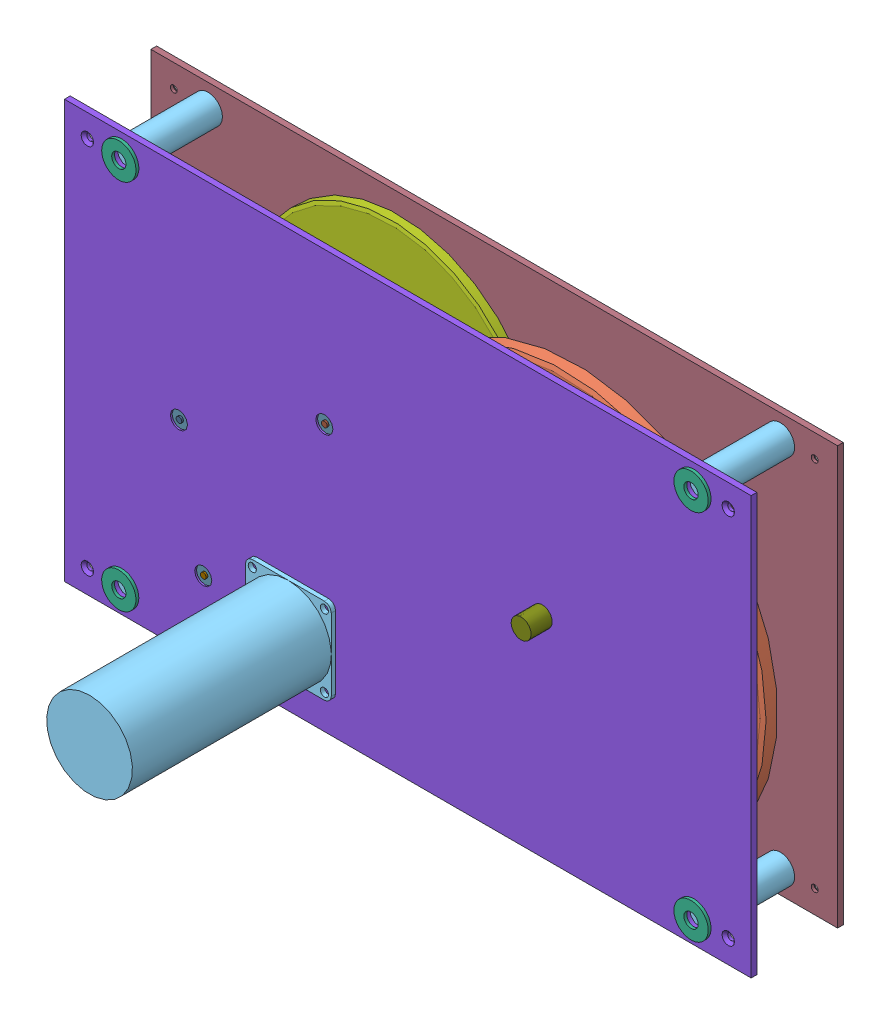
SolidWorks assembly Сборка1, configuration Полный. Lengths in mm.
Overall size (240 146 116.22).
42 component instances, 24 part files, 82 mates.
Components (placement in the parent):
- z1-1: z1 [Полный] at (79.7654 26 -7) x (-1 0 0) z (0 1 0) size (12.5 6 12.5)
- z2-1: z2 [Полный] at (48.5154 26 -3.75) x (1 0 0) z (0 1 0) size (51 8.48 51)
- z3-1: z3 [Полный] at (48.5154 26 -16.75) x (-1 0 0) z (0 1 0) size (13.5 6 13.5)
- z4-1: z4 [Полный] at (40 68.9133 -17) x (1 0 0) z (0 -1 0) size (75 7 75)
- ДПР-1: ДПР [Полный] at (79.7654 26 73) x (0 0 -1) z (0 1 0) size (84.5 30 30)
- z5-1: z5 [Полный] at (40 68.9133 -24) x (-1 0 0) z (0 1 0) size (13.5 6 13.5)
- z6-1: z6 [Полный] at (90.832 93 -24.25) x (-1 0 0) z (0 1 0) size (101 7 101)
- list1-1: list1 [Полный] at origin size (240 146 2)
- val2-1: val2 [Полный] at (48.5154 26 -31) size (7 7 32.21)
- val3-1: val3 [Полный] at (40 68.9133 -31) size (7 7 32.21)
- val4-1: val4 [Полный] at (90.832 93 -32.4148) x (0.998801 -0.04895 0) z (0 0 1) size (7 7 32.21)
- z7-1: z7 [Полный] at (90.832 93 -9.65) x (1 0 0) z (0 -1 0) size (18.9 8.4 18.9)
- list2-1: list2 [Полный] at (0 0 -30.2135) size (240 146 2)
- подш2-1: подш2 [Полный] at (48.5154 26 -0.6) x (0.999616 -0.027714 0) z (0 0 1) size (7.2 7.2 2)
- подш2-2: подш2 [Полный] at (40 68.9133 -0.6) x (0.987241 -0.15923 0) z (0 0 1) size (7.2 7.2 2)
- подш2-3: подш2 [Полный] at (90.832 93 -0.6) x (0.993287 -0.11568 0) z (0 0 1) size (7.2 7.2 2)
- подш2-5: подш2 [Полный] at (167 73 -0.6) x (0.605426 0.795902 0) z (0 0 1) size (7.2 7.2 2)
- подш2-6: подш2 [Полный] at (90.832 93 -27.6135) x (-0.923728 -0.383049 0) z (0 0 -1) size (7.2 7.2 2)
- подш2-7: подш2 [Полный] at (40 68.9133 -27.6135) x (-0.923728 -0.383049 0) z (0 0 -1) size (7.2 7.2 2)
- подш2-8: подш2 [Полный] at (48.5154 26 -27.6135) x (-0.923728 -0.383049 0) z (0 0 -1) size (7.2 7.2 2)
- mufta-1: mufta [Полный] at (167 73 -73.8912) x (0 0 -1) z (-1 0 0) size (51 141.4 141.4)
  - prushina-1: prushina [Полный] at (-61.987 0 0) x (0 0.715642 0.698468) z (1 0 0) size (18.92 18.98 26.11)
  - val5-1: val5 [Полный] at (-73.2912 0 0) x (0 -0.973244 -0.229772) z (1 0 0) size (15 15 51)
  - vt1-1: vt1 [Полный] at (-41.3486 0 0) x (0 -1 0) z (0 0 1) size (30 6 30)
  - vt2-1: vt2 [Полный] at (-56.8912 0 0) x (0 1 0) z (0 0 1) size (31 6 31)
  - disk-1: disk [Полный] at (-63.8912 0 0) x (0 0.969939 -0.24335) z (1 0 0) size (30 30 1)
  - подш2-1: подш2 [Полный] at (-35.2912 0 0) x (0 1 0) z (1 0 0) size (7.2 7.2 2)
  - z8-1: z8 [Полный] at (-63.8912 0 0) x (0 1 0) z (0 0 1) size (141.4 4.9 141.4)
- stakan-1: stakan [Полный] at (167 73 -28.566) x (1 0 0) z (0 1 0) size (48.86 14.66 48.86)
- гайка-1: гайка [Полный] at (79.7654 26 -8.1) x (0 0 1) z (-1 0 0) size (2.2 7 6.06)
- stoika-5: stoika [Полный] at (20 8 -28.2135) x (1 0 0) z (0 -1 0) size (10 28.21 10)
- stoika-6: stoika [Полный] at (20 138 -28.2135) x (1 0 0) z (0 -1 0) size (10 28.21 10)
- stoika-7: stoika [Полный] at (220 138 -28.2135) x (1 0 0) z (0 -1 0) size (10 28.21 10)
- stoika-8: stoika [Полный] at (220 8 -28.2135) x (1 0 0) z (0 -1 0) size (10 28.21 10)
- диск-1: диск [Полный] at (220 138 -31.2135) size (12 12 1)
- диск-2: диск [Полный] at (20 138 -31.2135) size (12 12 1)
- диск-3: диск [Полный] at (20 8 -31.2135) size (12 12 1)
- диск-4: диск [Полный] at (220 8 -31.2135) size (12 12 1)
- диск-5: диск [Полный] at (220 8 2) size (12 12 1)
- диск-6: диск [Полный] at (220 138 2) size (12 12 1)
- диск-7: диск [Полный] at (20 138 2) size (12 12 1)
- диск-8: диск [Полный] at (20 8 2) x (0.432232 0.901762 0) z (0 0 1) size (12 12 1)
Mates (geometry in assembly coordinates):
- Концентричный3: concentric aligned: cylinder of z2-1 through (48.5154 26 -10.75) axis (0 0 1) radius 2; cylinder of z3-1 through (48.5154 26 -16.75) axis (0 0 1) radius 2
- Концентричный5: concentric anti-aligned: cylinder of z4-1 through (40 68.9133 -10) axis (0 0 -1) radius 2; cylinder of z5-1 through (40 68.9133 -24) axis (0 0 1) radius 2
- Ширина2: width anti-aligned: plane of z3-1 through (48.5154 26 -16.75) normal (0 0 -1); plane of z4-1 through (41.7654 26 -13.75) normal (0 0 1); plane of z3-1 through (77.5 68.9133 -13.5) normal (0 0 1); plane of z4-1 through (40 68.9133 -17) normal (0 0 -1)
- Ширина3: width anti-aligned: plane of z5-1 through (40 68.9133 -24) normal (0 0 -1); plane of z6-1 through (33.25 68.9133 -21) normal (0 0 1); plane of z5-1 through (90.832 93 -24.25) normal (0 0 -1); plane of z6-1 through (40.332 93 -20.75) normal (0 0 1)
- Параллельность1: parallel aligned: plane of ДПР-1 through (64.7654 11 3.5) normal (-1 0 0); plane of list1-1 through (0 0 2) normal (-1 0 0)
- Совпадение6: coincident anti-aligned: plane of z1-1 through (76.7654 26 -1) normal (0 0 1); plane of ДПР-1 through (75.2535 26 -1) normal (0 0 -1)
- Концентричный6: concentric aligned: cylinder of z1-1 through (79.7654 26 -7) axis (0 0 1) radius 2; cylinder of ДПР-1 through (79.7654 26 73) axis (0 0 1) radius 2
- Совпадение7: coincident anti-aligned: plane of ДПР-1 through (64.7654 26 2) normal (0 0 -1); plane of list1-1 through (0 0 2) normal (0 0 1)
- Концентричный8: concentric aligned: cylinder of list1-1 through (48.5154 26 2) axis (0 0 -1) radius 3; cylinder of val2-1 through (48.5154 26 5.0569) axis (0 0 -1) radius 2
- Совпадение8: coincident aligned: plane of list1-1 through (0 0 2) normal (0 0 1); plane of val2-1 through (0 0 2) normal (0 0 1)
- Концентричный9: concentric anti-aligned: cylinder of z2-1 through (48.5154 26 -10.75) axis (0 0 1) radius 2; cylinder of val2-1 through (48.5154 26 5.0569) axis (0 0 -1) radius 2
- Ширина4: width anti-aligned: plane of z2-1 through (74.0154 26 -7.25) normal (0 0 -1); plane of z1-1 through (48.5154 26 -3.75) normal (0 0 1); plane of z2-1 through (73.5154 26 -4) normal (0 0 1); plane of z1-1 through (79.7654 26 -7) normal (0 0 -1)
- Совпадение9: coincident aligned: plane of list1-1 through (0 0 2) normal (0 0 1); plane of val3-1 through (0 0 2) normal (0 0 1)
- Концентричный14: concentric aligned: cylinder of z4-1 through (40 68.9133 -10) axis (0 0 -1) radius 2; cylinder of val3-1 through (40 68.9133 5.0569) axis (0 0 -1) radius 2
- Концентричный15: concentric anti-aligned: cylinder of z5-1 through (40 68.9133 -18) axis (0 0 1) radius 3; cylinder of val3-1 through (40 68.9133 5.0569) axis (0 0 -1) radius 2
- Концентричный16: concentric anti-aligned: cylinder of z6-1 through (90.832 93 -17.25) axis (0 0 1) radius 3; cylinder of val4-1 through (90.832 93 5.0569) axis (0 0 -1) radius 2
- Концентричный17: concentric anti-aligned: cylinder of val4-1 through (90.832 93 5.0569) axis (0 0 -1) radius 2; cylinder of z7-1 through (90.832 93 -1.25) axis (0 0 1) radius 3
- Совпадение12: coincident anti-aligned: plane of list1-1 through (0 0 0) normal (0 0 -1)
- Совпадение13: coincident anti-aligned: plane of list1-1 through (0 0 2) normal (0 -1 0)
- Совпадение14: coincident anti-aligned: plane of list1-1 through (0 0 2) normal (-1 0 0)
- Концентричный19: concentric anti-aligned: cylinder of val2-1 through (48.5154 26 -33.042) axis (0 0 1) radius 1; cylinder of list2-1 through (48.5154 26 -28.2135) axis (0 0 -1) radius 3
- Концентричный20: concentric anti-aligned: cylinder of val3-1 through (40 68.9133 -33.042) axis (0 0 1) radius 1; cylinder of list2-1 through (40 68.9133 -28.2135) axis (0 0 -1) radius 3
- Концентричный21: concentric aligned: cylinder of val2-1 through (48.5154 26 4.8284) axis (0 0 -1) radius 1; cylinder of подш2-1 through (48.5154 26 1.4) axis (0 0 -1) radius 3
- Совпадение16: coincident aligned: plane of list1-1 through (0 0 0) normal (0 0 -1); circle of подш2-1
- Концентричный22: concentric aligned: cylinder of val3-1 through (40 68.9133 4.8284) axis (0 0 -1) radius 1; cylinder of подш2-2 through (40 68.9133 1.4) axis (0 0 -1) radius 3
- Совпадение17: coincident anti-aligned: plane of list1-1 through (0 0 0) normal (0 0 -1); plane of подш2-2 through (40 68.9133 0) normal (0 0 1)
- Концентричный23: concentric aligned: cylinder of val4-1 through (90.832 93 4.8284) axis (0 0 -1) radius 1; cylinder of подш2-3 through (90.832 93 1.4) axis (0 0 -1) radius 3
- Совпадение18: coincident anti-aligned: plane of list1-1 through (0 0 0) normal (0 0 -1); plane of подш2-3 through (90.832 93 0) normal (0 0 1)
- Концентричный26: concentric aligned: cylinder of val4-1 through (90.832 93 -33.042) axis (0 0 1) radius 1; cylinder of подш2-6 through (90.832 93 -29.6135) axis (0 0 1) radius 3
- Совпадение21: coincident anti-aligned: plane of list2-1 through (0 0 -28.2135) normal (0 0 1); plane of подш2-6 through (90.832 93 -28.2135) normal (0 0 -1)
- Концентричный28: concentric aligned: cylinder of val3-1 through (40 68.9133 -33.042) axis (0 0 1) radius 1; cylinder of подш2-7 through (40 68.9133 -29.6135) axis (0 0 1) radius 3
- Совпадение22: coincident anti-aligned: plane of list2-1 through (0 0 -28.2135) normal (0 0 1); plane of подш2-7 through (40 68.9133 -28.2135) normal (0 0 -1)
- Концентричный30: concentric aligned: cylinder of val2-1 through (48.5154 26 -33.042) axis (0 0 1) radius 1; cylinder of подш2-8 through (48.5154 26 -29.6135) axis (0 0 1) radius 3
- Совпадение23: coincident anti-aligned: plane of list2-1 through (0 0 -28.2135) normal (0 0 1); plane of подш2-8 through (48.5154 26 -28.2135) normal (0 0 -1)
- Параллельность2: parallel aligned: plane of z1-1 through (79.7654 26 -7) normal (0 1 0); plane of list1-1 through (0 146 2) normal (0 1 0)
- Параллельность3: parallel aligned: plane of z2-1 through (48.5154 26 -3.75) normal (0 1 0); plane of list1-1 through (0 146 2) normal (0 1 0)
- Параллельность4: parallel aligned: plane of z3-1 through (48.5154 26 -16.75) normal (0 1 0); plane of list1-1 through (0 146 2) normal (0 1 0)
- Параллельность5: parallel anti-aligned: plane of z4-1 through (40 68.9133 -17) normal (0 -1 0); plane of list1-1 through (0 146 2) normal (0 1 0)
- Параллельность6: parallel aligned: plane of z5-1 through (40 68.9133 -24) normal (0 1 0); plane of list1-1 through (0 146 2) normal (0 1 0)
- Параллельность7: parallel aligned: plane of z6-1 through (90.832 93 -24.25) normal (0 1 0); plane of list1-1 through (0 146 2) normal (0 1 0)
- Параллельность8: parallel anti-aligned: plane of list1-1 through (0 146 2) normal (0 1 0); plane of z7-1 through (90.832 93 -9.65) normal (0 -1 0)
- Концентричный31: concentric aligned: cylinder of list1-1 through (167 73 2) axis (0 0 -1) radius 3; cylinder of mufta-1/val5-1 through (167 73 9.4) axis (0 0 -1) radius 3.5
- Ширина6: width anti-aligned: plane of mufta-1/z8-1 through (167 73 -10) normal (0 0 -1); plane of z7-1 through (167 2.3 -5.1) normal (0 0 1); plane of mufta-1/z8-1 through (90.832 93 -9.65) normal (0 0 -1); plane of z7-1 through (100.282 93 -5.45) normal (0 0 1)
- Параллельность11: parallel anti-aligned: plane of assembly through (0 0 0) normal (0 1 0); plane of mufta-1 through (167 73 -73.8912) normal (0 -1 0)
- Концентричный32: concentric anti-aligned: cylinder of list1-1 through (167 73 2) axis (0 0 -1) radius 3; circle of подш2-5
- Совпадение24: coincident anti-aligned: plane of list1-1 through (0 0 0) normal (0 0 -1); plane of подш2-5 through (167 73 0) normal (0 0 1)
- Совпадение27: coincident anti-aligned: plane of z2-1 through (51.5154 26 -10.75) normal (0 0 -1); plane of z3-1 through (45.5154 26 -10.75) normal (0 0 1)
- Расстояние1: distance = 1 mm anti-aligned: plane of z4-1 through (40 68.9133 -17) normal (0 0 -1); plane of z5-1 through (37 68.9133 -18) normal (0 0 1)
- Концентричный34: concentric aligned: cylinder of list1-1 through (90.832 93 2) axis (0 0 -1) radius 3; cylinder of val4-1 through (90.832 93 5.0569) axis (0 0 -1) radius 2
- Концентричный35: concentric aligned: cylinder of list1-1 through (40 68.9133 2) axis (0 0 -1) radius 3; cylinder of val3-1 through (40 68.9133 5.0569) axis (0 0 -1) radius 2
- Концентричный36: concentric aligned: cylinder of list1-1 through (48.5154 26 2) axis (0 0 -1) radius 3; cylinder of val2-1 through (48.5154 26 5.0569) axis (0 0 -1) radius 2
- Совпадение31: coincident anti-aligned: plane of z1-1 through (79.7654 26 -7) normal (0 0 -1); plane of гайка-1 through (79.7654 28 -7) normal (0 0 1)
- Параллельность12: parallel anti-aligned: plane of гайка-1 through (79.7654 26 -8.1) normal (-1 0 0)
- Концентричный38: concentric anti-aligned: cylinder of ДПР-1 through (79.7654 26 73) axis (0 0 1) radius 2; cylinder of гайка-1 through (79.7654 26 -10.8853) axis (0 0 -1) radius 2
- Концентричный39: concentric anti-aligned: cylinder of ДПР-1 through (79.7654 26 73) axis (0 0 1) radius 11; cylinder of list1-1 through (79.7654 26 2) axis (0 0 -1) radius 11
- Совпадение32: coincident anti-aligned: plane of list2-1 through (0 0 -28.2135) normal (0 0 1); plane of stoika-5 through (20 8 -28.2135) normal (0 0 -1)
- Концентричный40: concentric aligned: cylinder of list2-1 through (20 8 -28.2135) axis (0 0 -1) radius 3.5; cylinder of stoika-5 through (20 8 14.1421) axis (0 0 -1) radius 5
- Совпадение33: coincident anti-aligned: plane of list2-1 through (0 0 -28.2135) normal (0 0 1); plane of stoika-6 through (20 138 -28.2135) normal (0 0 -1)
- Концентричный41: concentric anti-aligned: circle of list2-1; cylinder of stoika-6 through (20 138 14.1421) axis (0 0 -1) radius 5
- Совпадение34: coincident anti-aligned: plane of list2-1 through (0 0 -28.2135) normal (0 0 1); plane of stoika-7 through (220 138 -28.2135) normal (0 0 -1)
- Концентричный42: concentric aligned: cylinder of list2-1 through (220 138 -28.2135) axis (0 0 -1) radius 3.5; cylinder of stoika-7 through (220 138 14.1421) axis (0 0 -1) radius 5
- Совпадение35: coincident anti-aligned: plane of list2-1 through (0 0 -28.2135) normal (0 0 1); plane of stoika-8 through (220 8 -28.2135) normal (0 0 -1)
- Концентричный43: concentric aligned: cylinder of list2-1 through (220 8 -28.2135) axis (0 0 -1) radius 3.5; cylinder of stoika-8 through (220 8 14.1421) axis (0 0 -1) radius 5
- Совпадение36: coincident anti-aligned: plane of list2-1 through (0 0 -30.2135) normal (0 0 -1); plane of диск-1 through (220 138 -30.2135) normal (0 0 1)
- Концентричный44: concentric aligned: cylinder of list2-1 through (220 138 -28.2135) axis (0 0 -1) radius 3.5; cylinder of диск-1 through (220 138 -30.2135) axis (0 0 -1) radius 2.5
- Совпадение37: coincident anti-aligned: plane of list2-1 through (0 0 -30.2135) normal (0 0 -1); plane of диск-2 through (20 138 -30.2135) normal (0 0 1)
- Концентричный45: concentric aligned: cylinder of list2-1 through (20 138 -28.2135) axis (0 0 -1) radius 3.5; cylinder of диск-2 through (20 138 -30.2135) axis (0 0 -1) radius 2.5
- Совпадение39: coincident anti-aligned: plane of list2-1 through (0 0 -30.2135) normal (0 0 -1); plane of диск-3 through (20 8 -30.2135) normal (0 0 1)
- Концентричный46: concentric aligned: cylinder of list2-1 through (20 8 -28.2135) axis (0 0 -1) radius 3.5; cylinder of диск-3 through (20 8 -30.2135) axis (0 0 -1) radius 2.5
- Совпадение40: coincident anti-aligned: plane of list2-1 through (0 0 -30.2135) normal (0 0 -1); plane of диск-4 through (220 8 -30.2135) normal (0 0 1)
- Концентричный47: concentric aligned: cylinder of list2-1 through (220 8 -28.2135) axis (0 0 -1) radius 3.5; cylinder of диск-4 through (220 8 -30.2135) axis (0 0 -1) radius 2.5
- Совпадение41: coincident anti-aligned: plane of list1-1 through (0 0 2) normal (0 0 1); plane of диск-5 through (220 8 2) normal (0 0 -1)
- Концентричный48: concentric aligned: cylinder of list1-1 through (220 8 2) axis (0 0 -1) radius 3.5; cylinder of диск-5 through (220 8 3) axis (0 0 -1) radius 2.5
- Совпадение42: coincident anti-aligned: plane of list1-1 through (0 0 2) normal (0 0 1); plane of диск-6 through (220 138 2) normal (0 0 -1)
- Концентричный49: concentric aligned: cylinder of list1-1 through (220 138 2) axis (0 0 -1) radius 3.5; cylinder of диск-6 through (220 138 3) axis (0 0 -1) radius 2.5
- Совпадение43: coincident anti-aligned: plane of list1-1 through (0 0 2) normal (0 0 1); plane of диск-7 through (20 138 2) normal (0 0 -1)
- Концентричный50: concentric aligned: cylinder of list1-1 through (20 138 2) axis (0 0 -1) radius 3.5; cylinder of диск-7 through (20 138 3) axis (0 0 -1) radius 2.5
- Концентричный51: concentric aligned: cylinder of list1-1 through (20 8 2) axis (0 0 -1) radius 3.5; cylinder of диск-8 through (20 8 3) axis (0 0 -1) radius 2.5
- Совпадение45: coincident anti-aligned: plane of list1-1 through (0 0 2) normal (0 0 1); plane of диск-8 through (20 8 2) normal (0 0 -1)
- Совпадение46: coincident anti-aligned: plane of подш2-5 through (167 73 -0.6) normal (0 0 -1); plane of mufta-1/val5-1 through (167 73 -0.6) normal (0 0 1)
- Совпадение47: coincident anti-aligned: plane of list2-1 through (0 0 -30.2135) normal (0 0 -1); plane of stakan-1 through (185 73 -30.2135) normal (0 0 1)
- Концентричный52: concentric aligned: cylinder of mufta-1/val5-1 through (167 73 -41.6) axis (0 0 1) radius 3.5; cylinder of stakan-1 through (167 73 -28.566) axis (0 0 1) radius 4
